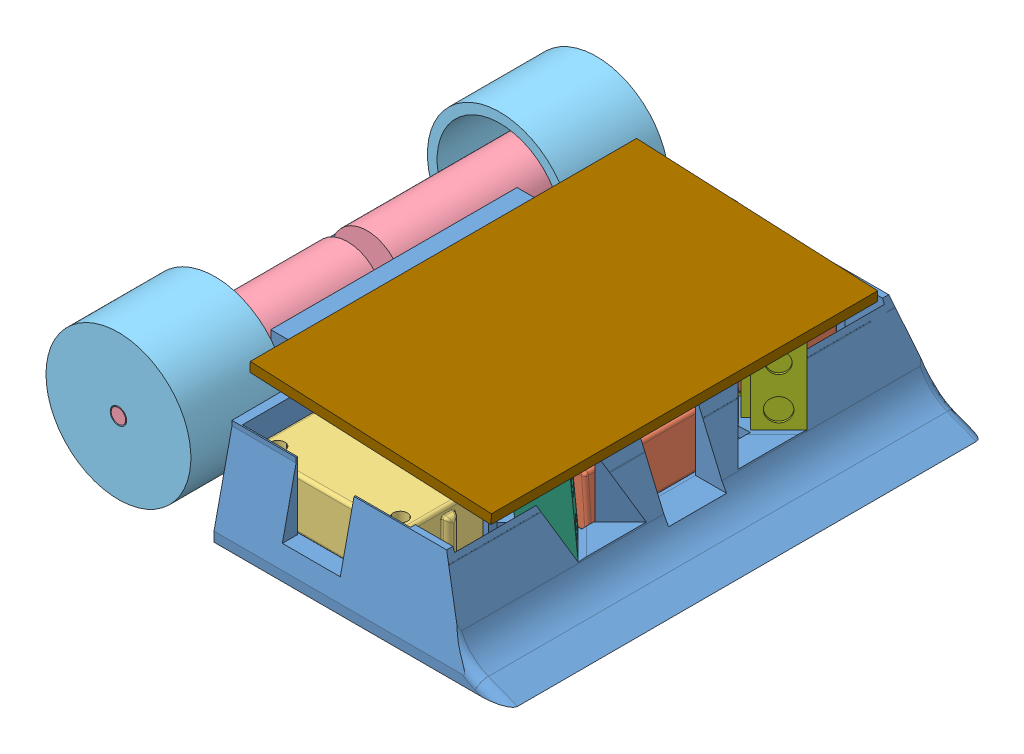
SolidWorks assembly Assemson, configuration Default. Lengths in mm.
Overall size (95.68 30 100.4).
12 component instances, 9 part files, 27 mates.
Components (placement in the parent):
- sharplı full-1: sharplı full [Default] at (-72.2668 9.9692 26.9725) size (90.88 20 100.4)
- omron4 - Copy-1: omron4 - Copy [Default] at (-45.2987 23.7692 -21.4454) x (-1 0 0) z (0 0 1) size (37.72 10.8 25.16)
- omron4 - Copy-2: omron4 - Copy [Default] at (-30.6311 12.2134 14.0346) x (0 0 1) z (-0.997575 -0.069598 0) size (37.72 10.8 25.16)
- omron4-1: omron4 [Default] at (-45.2987 12.9692 49.5546) x (-1 0 0) z (0 0 -1) size (37.72 10.8 25.16)
- faullhabber-1: faullhabber [Default] at (-46.3085 3.3472 11.0546) x (0 0 1) z (-0.994867 -0.101187 0) size (47.5 15 15)
- faullhabber-2: faullhabber [Default] at (-119.7939 -0.3803 17.0546) x (0 0 -1) z (1 0 0) size (47.5 15 15)
- tekerlek-1: tekerlek [Default] at (-83.9762 19.7192 -15.4454) x (0 0 -1) z (1 0 0) size (20 30 30)
- tekerlek-2: tekerlek [Default] at (-83.9762 19.7192 43.5546) x (0 0 1) z (-1 0 0) size (20 30 30)
- sharp - Copy-1: sharp - Copy [Default] at (-29.7309 21.637 23.2979) x (-0.707107 0 -0.707107) z (-0.0538 0.997101 0.0538) size (12.7 8.7 15)
- sharp - Copy - Copy-1: sharp - Copy - Copy [Default] at (-29.8086 23.0767 3.9471) x (-0.707107 0 0.707107) z (0.0538 -0.997101 0.0538) size (12.7 8.7 15)
- batarya-1: batarya [Default] at (-66.1014 9.9692 -5.2125) x (0 0 -1) z (1 0 0) size (42 20 23)
- kart-1: kart [Default] at (-44.2559 31.1825 8.7532) x (0 0 -1) z (0.998882 -0.047264 0) size (80 2 50)
Mates (geometry in assembly coordinates):
- Coincident1: coincident anti-aligned: plane of omron4 - Copy-1 through (-45.2987 12.9692 -21.4454) normal (0 -1 0); plane of sharplı full-1 through (-72.2668 12.9692 26.9725) normal (0 1 0)
- Coincident2: coincident anti-aligned: plane of sharplı full-1 through (-62.2987 12.9692 -31.4454) normal (0 0 1); plane of omron4 - Copy-1 through (-29.7987 12.9692 -31.4454) normal (0 0 -1)
- Concentric4: concentric: circle of sharplı full-1; circle of omron4 - Copy-1
- Coincident3: coincident anti-aligned: plane of sharplı full-1 through (-19.7987 12.9692 -3.7454) normal (-0.069598 0.997575 0); plane of omron4 - Copy-2 through (-30.6311 12.2134 14.0346) normal (0.069598 -0.997575 0)
- Parallel2: parallel anti-aligned: line of sharplı full-1 through (-20.3552 12.9304 7.6611) axis (0 0 1); line of omron4 - Copy-2 through (-22.1053 23.6345 28.8346) axis (0 0 -1)
- Coincident8: coincident anti-aligned: plane of sharplı full-1 through (-62.2987 12.9692 59.5546) normal (0 0 -1); plane of omron4-1 through (-29.7987 23.7692 59.5546) normal (0 0 1)
- Coincident9: coincident anti-aligned: plane of sharplı full-1 through (-72.2668 12.9692 26.9725) normal (0 1 0); plane of omron4-1 through (-45.2987 12.9692 49.5546) normal (0 -1 0)
- Concentric6: concentric: circle of sharplı full-1; circle of omron4-1
- Concentric7: concentric anti-aligned: cylinder of sharplı full-1 through (-83.9762 19.7192 -40.4454) axis (0 0 1) radius 7.55; cylinder of faullhabber-1 through (-83.9762 19.7192 56.0546) axis (0 0 -1) radius 7.5
- Coincident10: coincident aligned: plane of sharplı full-1 through (-64.1771 7.9692 63.5546) normal (0 0 1); plane of faullhabber-1 through (-83.925 19.775 63.5546) normal (0 0 1)
- Concentric8: concentric aligned: cylinder of sharplı full-1 through (-83.9762 19.7192 -40.4454) axis (0 0 1) radius 7.55; cylinder of faullhabber-2 through (-83.9762 19.7192 -27.9454) axis (0 0 1) radius 7.5
- Coincident11: coincident: line of sharplı full-1 through (-64.1771 6.9692 -35.4454) axis (1 0 0); plane of faullhabber-2 through (-84.0327 19.7695 -35.4454) normal (0 0 -1)
- Concentric9: concentric anti-aligned: cylinder of faullhabber-2 through (-83.9762 19.7192 -42.9454) axis (0 0 1) radius 1.5; cylinder of tekerlek-1 through (-83.9762 19.7192 -33.4454) axis (0 0 -1) radius 1.7
- Coincident12: coincident aligned: plane of faullhabber-2 through (-84.0327 19.7695 -35.4454) normal (0 0 -1); plane of tekerlek-1 through (-83.9762 19.7192 -35.4454) normal (0 0 -1)
- Concentric10: concentric anti-aligned: cylinder of faullhabber-1 through (-83.9762 19.7192 71.0546) axis (0 0 -1) radius 1.5; cylinder of tekerlek-2 through (-83.9762 19.7192 61.5546) axis (0 0 1) radius 1.7
- Coincident13: coincident aligned: plane of faullhabber-1 through (-83.925 19.775 63.5546) normal (0 0 1); plane of tekerlek-2 through (-83.9762 19.7192 63.5546) normal (0 0 1)
- Coincident14: coincident anti-aligned: plane of sharplı full-1 through (-21.2031 14.9692 29.4169) normal (-0.0538 0.997101 0.0538); plane of sharp - Copy-1 through (-17.5805 14.597 39.9364) normal (0.0538 -0.997101 -0.0538)
- Coincident15: coincident anti-aligned: plane of sharp - Copy-1 through (-17.5805 14.597 39.9364) normal (0.707107 0 0.707107); plane of sharplı full-1 through (-23.3987 14.9692 45.7546) normal (-0.707107 0 -0.707107)
- Coincident16: coincident: point of sharplı full-1; point of sharp - Copy-1
- Coincident20: coincident anti-aligned: plane of sharplı full-1 through (-23.3987 24.4104 -18.4319) normal (-0.707107 0 0.707107); plane of sharp - Copy - Copy-1 through (-18.3875 29.5536 -13.4207) normal (0.707107 0 -0.707107)
- Coincident21: coincident anti-aligned: plane of sharplı full-1 through (-30.4697 13.9692 -11.3609) normal (-0.0538 0.997101 -0.0538); plane of sharp - Copy - Copy-1 through (-17.5805 14.597 -12.6137) normal (0.0538 -0.997101 0.0538)
- Coincident22: coincident: point of sharplı full-1; point of sharp - Copy - Copy-1
- Coincident23: coincident anti-aligned: plane of sharplı full-1 through (-72.2668 9.9692 26.9725) normal (0 1 0); plane of batarya-1 through (-66.1014 9.9692 -5.2125) normal (0 -1 0)
- Coincident25: coincident anti-aligned: plane of sharplı full-1 through (-69.2987 12.9692 37.5546) normal (1 0 0); plane of batarya-1 through (-69.2987 29.9692 34.9029) normal (-1 0 0)
- Coincident26: coincident: plane of batarya-1 through (-66.1014 29.9692 -5.2125) normal (0 1 0); plane of kart-1
- Parallel3: parallel aligned: line of sharplı full-1 through (-13.9125 12.9304 19.6611) axis (0 0 -1); line of kart-1 through (-15.6842 31.8328 54.5883) axis (0 0 -1)
- Coincident29: coincident: point of sharp - Copy-1; line of kart-1 through (-15.7788 29.8351 54.5883) axis (0 0 -1)
